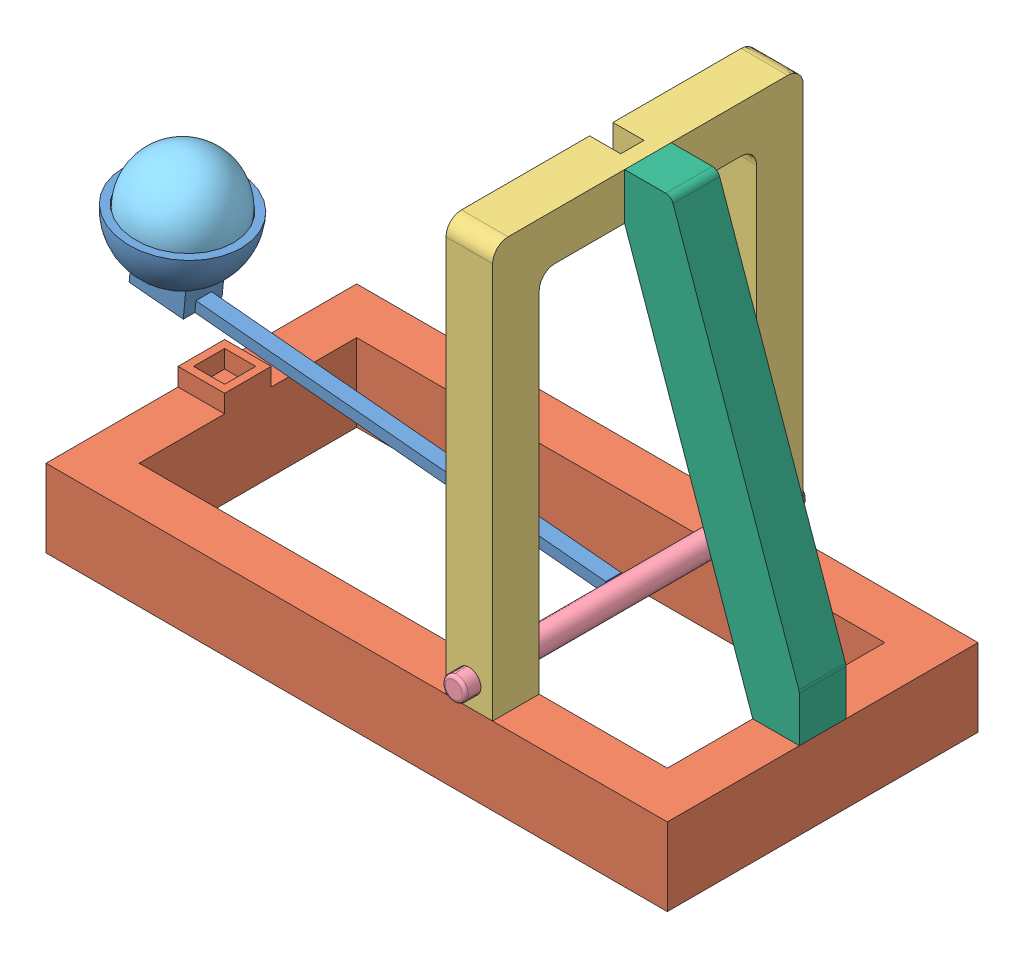
SolidWorks assembly Assembly_Throwing_Arm, configuration Default. Lengths in mm.
Overall size (454.4 315 220).
6 component instances, 6 part files, 17 mates.
Components (placement in the parent):
- Arm-1: Arm [Default] at (-412.0813 136.3671 -0.005) x (0 0 1) z (-0.093332 -0.995635 0) size (76 320.5 48)
- Base-1: Base [Default] at (-205.4167 50 0) x (1 0 0) z (0 -1 0) size (400 200 61.5)
- Frame-1: Frame [Default] at (-142.5 137.8818 -7.931) x (0 0 -1) z (1 0 0) size (200 305 30)
- Shaft-1: Shaft [Default] at (-127.5 65 110) x (-0.093332 -0.995635 0) z (0 0 -1) size (15 257.5 220)
- Ball-1: Ball [Default] at (-412.0813 136.3671 -0.005) x (0.971274 0.07617 -0.225442) z (0.21567 0.118582 0.969239) size (65 65 65)
- Support_TA-2: Support_TA [Default] at (0 50 -15.0002) size (122.5 305 30)
Mates (geometry in assembly coordinates):
- Coincident1: coincident: plane of Base-1 through (-205.4167 10 0) normal (0 1 0); plane of Frame-1 through (-142.5 10 -7.931) normal (0 -1 0)
- Coincident2: coincident: plane of Base-1 through (-205.4167 10 0) normal (0 1 0); plane of Frame-1 through (-142.5 10 -7.931) normal (0 -1 0)
- Coincident3: coincident: plane of Base-1 through (-135 10 92.5) normal (0 0 -1); plane of Frame-1 through (-120 10 92.5) normal (0 0 1)
- Coincident4: coincident: line of Base-1 through (-120 10 92.5) axis (0 1 0); line of Frame-1 through (-120 10 92.5) axis (0 1 0)
- Coincident7: coincident: plane of Arm-1 through (-398.601 92.6683 3.495) normal (0 0 -1); plane of Shaft-1 through (-119.8222 66.5351 3.495) normal (0 0 1)
- Coincident8: coincident: plane of Arm-1 through (-398.601 92.6683 3.495) normal (-0.093332 -0.995635 0); plane of Shaft-1 through (-119.8222 66.5351 3.495) normal (0.093332 0.995635 0)
- Tangent2: tangent: plane of Arm-1 through (-134.6411 69.1797 -5.005) normal (0.995635 -0.093332 0); cylinder of Shaft-1 through (-127.5 65 -110) axis (0 0 1) radius 7.5
- Concentric1: concentric: cylinder of Frame-1 through (-127.5 65 100) axis (0 0 -1) radius 7.5; cylinder of Shaft-1 through (-127.5 65 -110) axis (0 0 1) radius 7.5
- Width1: width: plane of Shaft-1 through (-127.5 65 110) normal (0 0 1); plane of Shaft-1 through (-127.5 65 -110) normal (0 0 -1); plane of Frame-1 through (-112.5 50 100) normal (0 0 1); plane of Frame-1 through (-112.5 315 -100) normal (0 0 -1)
- Parallel2: parallel: plane of Arm-1; plane of Base-1
- Coincident15: coincident: plane of Frame-1 through (-112.5 137.8818 -7.931) normal (1 0 0); plane of Support_TA-2 through (-112.5 285 14.9998) normal (-1 0 0)
- Width5: width: plane of Support_TA-2 through (-122.5 307.49 7.4898) normal (0 0 1); plane of Support_TA-2 through (-122.5 307.49 -7.4902) normal (0 0 -1); plane of Frame-1 through (-122.5 285 7.4998) normal (0 0 -1); plane of Frame-1 through (-122.5 285 -7.5002) normal (0 0 1)
- Coincident16: coincident: plane of Base-1 through (-205.4167 10 0) normal (0 1 0); plane of Support_TA-2 through (0 10 -15.0002) normal (0 -1 0)
- Coincident19: coincident: point of Base-1; point of assembly
- Concentric3: concentric: sphere of Arm-1; sphere of Ball-1
- Coincident20: coincident: plane of Base-1 through (-205.4167 0 0) normal (0 -1 0); plane of assembly through (0 0 0) normal (0 1 0)
- Parallel3: parallel: plane of Base-1 through (0 0 100) normal (0 0 1); plane of assembly through (0 0 0) normal (0 0 1)
